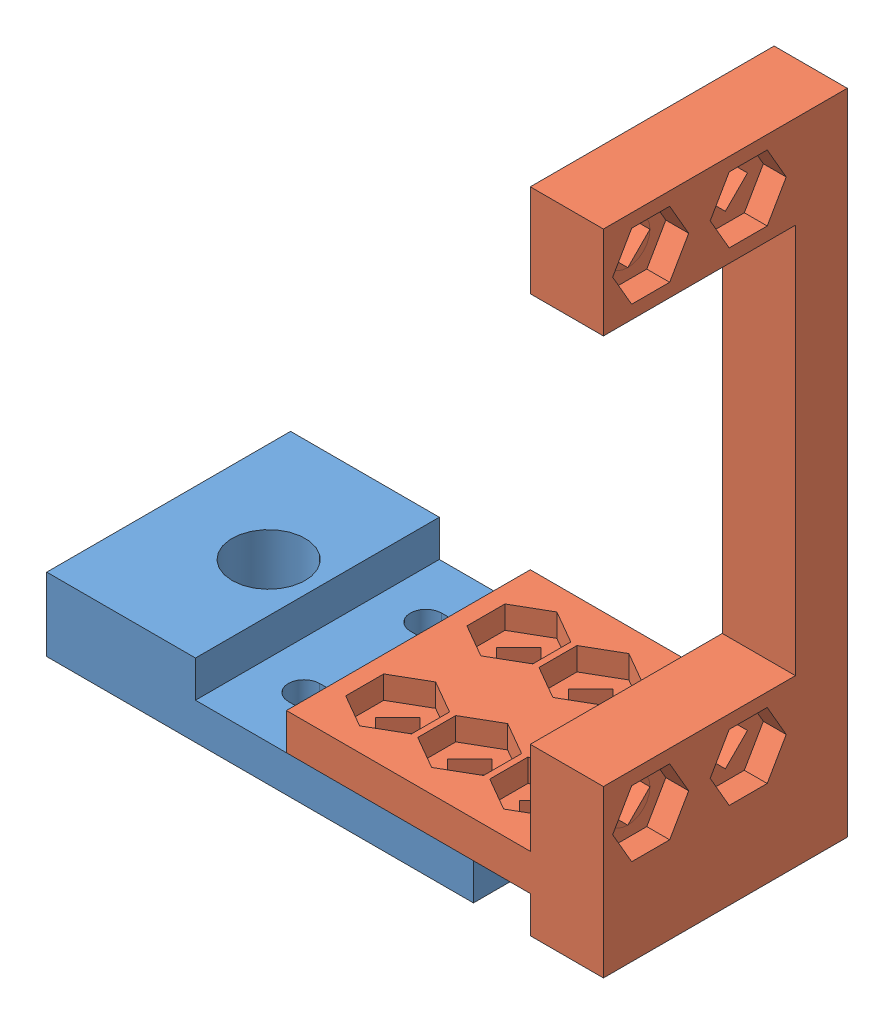
SolidWorks assembly YawArmAssembly, configuration Default. Lengths in mm.
Overall size (57.99 67.56 25.4).
2 component instances, 2 part files, 6 mates.
Components (placement in the parent):
- YawArm-YawServoAttachment-1: YawArm-YawServoAttachment [Default] at origin size (44.45 7.62 25.4)
- YawArm-PitchServoAttachment-1: YawArm-PitchServoAttachment [Default] at (28.1432 7.62 0) x (1 0 0) z (0 -1 0) size (33.02 25.4 67.56)
Mates (geometry in assembly coordinates):
- Coincident1: coincident anti-aligned: plane of YawArm-YawServoAttachment-1 through (22.225 0 12.7) normal (0 -1 0); plane of assembly through (0 0 0) normal (0 1 0)
- Symmetric1: symmetric aligned: plane of YawArm-YawServoAttachment-1 through (0 0 12.7) normal (0 0 1); plane of YawArm-YawServoAttachment-1 through (0 0 -12.7) normal (0 0 -1); plane of assembly through (0 0 0) normal (0 0 1)
- Symmetric2: symmetric aligned: plane of YawArm-YawServoAttachment-1 through (-22.225 0 12.7) normal (-1 0 0); plane of YawArm-YawServoAttachment-1 through (22.225 3.81 12.7) normal (1 0 0); plane of assembly through (0 0 0) normal (1 0 0)
- Coincident2: coincident anti-aligned: plane of YawArm-YawServoAttachment-1 through (-6.731 3.81 12.7) normal (0 1 0); plane of YawArm-PitchServoAttachment-1 through (-6.731 3.81 -12.7) normal (0 -1 0)
- Coincident3: coincident aligned: plane of YawArm-YawServoAttachment-1 through (0 0 12.7) normal (0 0 1); plane of YawArm-PitchServoAttachment-1 through (18.669 7.62 12.7) normal (0 0 1)
- Distance2: distance = 9.4742 mm anti-aligned: plane of YawArm-YawServoAttachment-1 through (-6.731 7.62 12.7) normal (1 0 0); plane of YawArm-PitchServoAttachment-1 through (2.7432 7.62 12.7) normal (-1 0 0)
